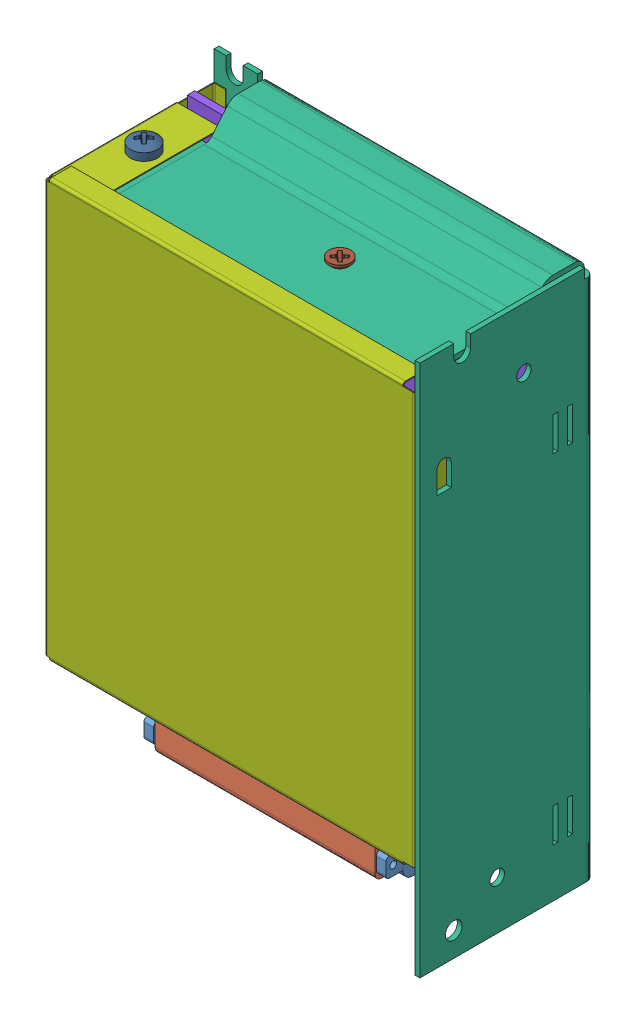
SolidWorks assembly S-60-12, configuration Default. Lengths in mm.
Overall size (77.5 110 36).
28 component instances, 13 part files, 0 mates.
Components (placement in the parent):
- S-60-12.step-1: S-60-12.step [Default] at origin size (77.5 110 36)
  - Model.step-1: Model.step [Default] at (-4 -46.5 7.5) size (50.04 16.01 22.51)
    - Body.step-1: Body.step [Default] at origin size (50.04 16.01 17.01)
    - Body-0.step-1: Body-0.step [Default] at (0 0 15.5) size (47.4 15 3)
    - Body-1.step-1: Body-1.step [Default] at (-19 -1.05 9.3) size (8 10.9 14.8)
    - Body-1.step-2: Body-1.step [Default] at (-9.5 -1.05 9.3) size (8 10.9 14.8)
    - Body-1.step-3: Body-1.step [Default] at (0 -1.05 9.3) size (8 10.9 14.8)
    - Body-1.step-4: Body-1.step [Default] at (9.5 -1.05 9.3) size (8 10.9 14.8)
    - Body-1.step-5: Body-1.step [Default] at (19 -1.05 9.3) size (8 10.9 14.8)
    - Body-2.step-1: Body-2.step [Default] at (-19 -1.05 9.4231) x (0 -1 0) z (0 0 1) size (9.8 9.8 1.86)
    - Body-2.step-2: Body-2.step [Default] at (-9.5 -1.05 9.4231) x (0 -1 0) z (0 0 1) size (9.8 9.8 1.86)
    - Body-2.step-3: Body-2.step [Default] at (0 -1.05 9.4231) x (0 -1 0) z (0 0 1) size (9.8 9.8 1.86)
    - Body-2.step-4: Body-2.step [Default] at (9.5 -1.05 9.4231) x (0 -1 0) z (0 0 1) size (9.8 9.8 1.86)
    - Body-2.step-5: Body-2.step [Default] at (19 -1.05 9.4231) x (0 -1 0) z (0 0 1) size (9.8 9.8 1.86)
    - Body-3.step-1: Body-3.step [Default] at (-19 -1.05 11.2846) x (0 -1 0) z (0 0 1) size (7.13 7.13 9.28)
    - Body-3.step-2: Body-3.step [Default] at (-9.5 -1.05 11.2846) x (0 -1 0) z (0 0 1) size (7.13 7.13 9.28)
    - Body-3.step-3: Body-3.step [Default] at (0 -1.05 11.2846) x (0 -1 0) z (0 0 1) size (7.13 7.13 9.28)
    - Body-3.step-4: Body-3.step [Default] at (9.5 -1.05 11.2846) x (0 -1 0) z (0 0 1) size (7.13 7.13 9.28)
    - Body-3.step-5: Body-3.step [Default] at (19 -1.05 11.2846) x (0 -1 0) z (0 0 1) size (7.13 7.13 9.28)
    - Contact_1.step-1: Contact_1.step [Default] at (-19 4 0) (suppressed, hidden)
  - Body-4.step-1: Body-4.step [Default] at origin size (77.5 110 36)
  - Body-5.step-1: Body-5.step [Default] at (0.25 6.5837 36) size (76.5 104.5 35)
  - Body-6.step-1: Body-6.step [Default] at (0.5 -2 6) size (75 105 1.5)
  - Potentiometer_Blue.step-1: Potentiometer_Blue.step [Default] at (25.4437 -49.9766 10.5) x (0 1 0) z (0 0 1) size (7.2 6.6 9)
  - M3x5-Screw.step-1: M3x5-Screw.step [Default] at (-33 -50.2163 7.7) x (-1 0 0) z (0 0 1) size (5.6 5.6 7.35)
  - M3x5-Screw.step-2: M3x5-Screw.step [Default] at (-32.5 49.5837 21) x (1 0 0) z (0 1 0) size (5.6 5.6 7.35)
  - M2.5x4-Screw.step-1: M2.5x4-Screw.step [Default] at (7.5 50.3837 20.5321) x (1 0 0) z (0 1 0) size (4.5 4.5 4)
  - Open CASCADE STEP translator 7.4 1.9.step-1: Open CASCADE STEP translator 7.4 1.9.step [Default] at origin
